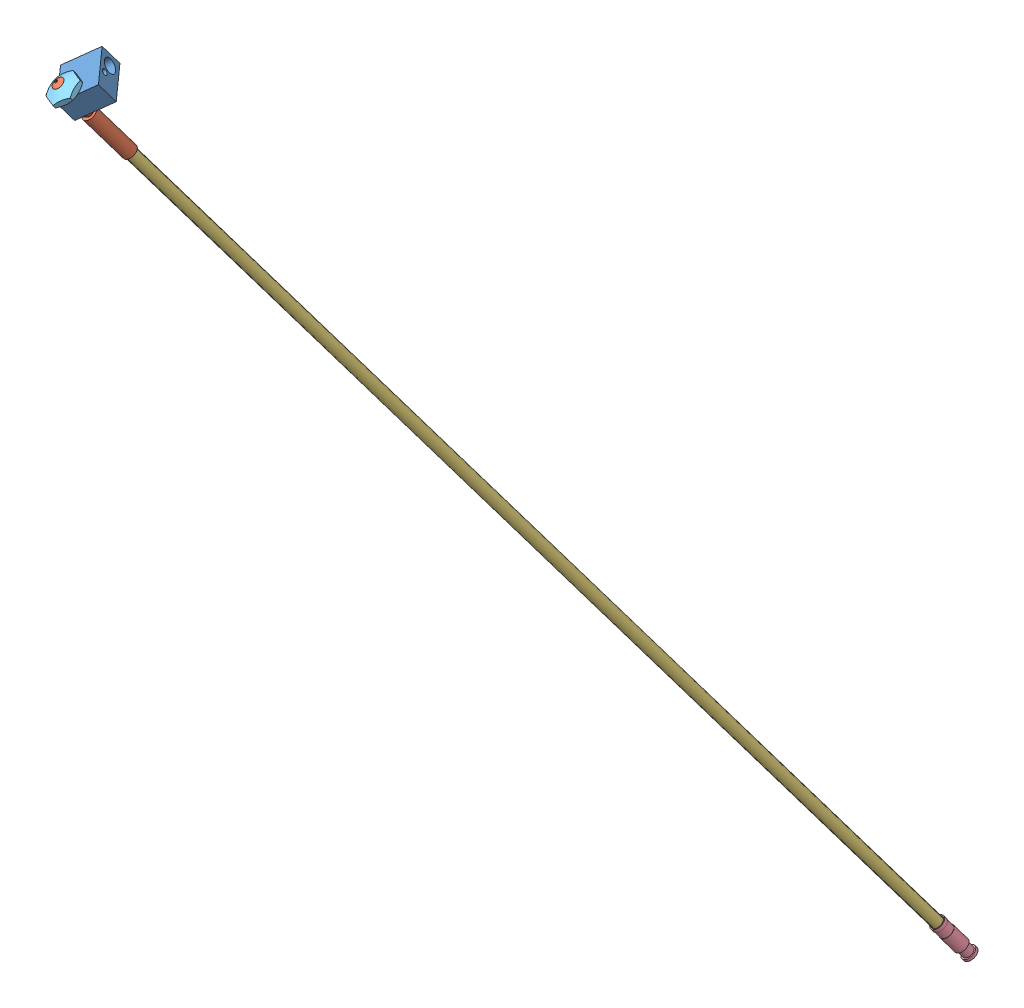
SolidWorks assembly 993, configuration SINGLE. Lengths in mm.
Overall size (146.61 331.74 220.5).
5 component instances, 5 part files, 89 mates.
Components (placement in the parent):
- 739-1: 739 [Default] at (90.2092 -3.5557 74.9658) x (-0.694987 -0.573024 0.434323) z (-0.330371 0.790997 0.514955)
- 738-2: 738 [Default] at (96.5193 -28.8096 77.071) x (0.082226 -0.519395 0.850569) z (-0.330371 0.790997 0.514955)
- 219-2: 219 [Default] at (219.3094 -322.8026 -114.3244) x (0.896188 0.091701 0.434094) z (-0.330371 0.790997 0.514955)
- 106-1: 106 [Default] at (216.207 -315.3746 -109.4887) x (0.541182 0.605747 -0.58326) z (0.330371 -0.790997 -0.514955)
- 794-1: 794 [Default] at (86.9463 -5.8894 91.9925) x (0.896188 0.091701 0.434094) z (-0.330371 0.790997 0.514955)
Mates (geometry in assembly coordinates):
- Coincident327: coincident anti-aligned: circle of 738-2; plane of ? through (56.8348 7.8683 60.6713) normal (-0.330371 0.790997 0.514955)
- Concentric245: concentric anti-aligned: cylinder of 739-1 through (86.9463 -5.8894 91.9925) axis (-0.330371 0.790997 0.514955) radius 1.65; cylinder of 738-2 through (96.5193 -28.8096 77.071) axis (0.330371 -0.790997 -0.514955) radius 2.5
- Concentric246: concentric anti-aligned: cylinder of ? through (58.2631 4.2288 58.0487) axis (-0.330371 0.790997 0.514955) radius 1.65; cylinder of ? through (67.8361 -18.6914 43.1272) axis (0.330371 -0.790997 -0.514955) radius 2
- Coincident331: coincident anti-aligned: plane of 739-1 through (99.15 -6.5573 85.3124) normal (0.330371 -0.790997 -0.514955); plane of 738-2 through (89.7784 -13.412 89.8292) normal (-0.330371 0.790997 0.514955)
- Coincident333: coincident anti-aligned: plane of ? through (59.0492 -34.3813 59.0199) normal (0.694987 0.573024 -0.434323); plane of ? through (59.0492 -34.3813 59.0199) normal (-0.694987 -0.573024 0.434323)
- Coincident335: coincident aligned: plane of 739-1 through (63.4764 -11.8319 70.5279) normal (0.330371 -0.790997 -0.514955); plane of ? through (51.3453 -7.7593 56.4895) normal (0.330371 -0.790997 -0.514955)
- Concentric259: concentric anti-aligned: cylinder of ? through (72.0249 -16.2373 53.0678) axis (-0.330371 0.790997 0.514955) radius 2.2; cylinder of ? through (70.0426 -11.4913 56.1575) axis (0.330371 -0.790997 -0.514955) radius 1.5
- Distance2: distance = 10 mm anti-aligned: plane of ? through (75.3286 -24.1473 47.9182) normal (-0.330371 0.790997 0.514955); plane of ? through (71.3313 -16.8108 53.5038) normal (0.330371 -0.790997 -0.514955)
- Coincident345: coincident anti-aligned: plane of ? through (59.0492 -34.3813 59.0199) normal (0.694987 0.573024 -0.434323); plane of ? through (59.0492 -34.3813 59.0199) normal (-0.694987 -0.573024 0.434323)
- Concentric263: concentric aligned: cylinder of ? through (38.6803 -22.3061 58.4748) axis (-0.694987 -0.573024 0.434323) radius 3.1; cylinder of ? through (47.0201 -15.4298 53.2629) axis (-0.694987 -0.573024 0.434323) radius 1.6
- Concentric264: concentric aligned: cylinder of ? through (59.1164 -29.1669 82.1241) axis (-0.694987 -0.573024 0.434323) radius 3.1; cylinder of ? through (67.4563 -22.2906 76.9122) axis (-0.694987 -0.573024 0.434323) radius 1.6
- Concentric265: concentric anti-aligned: cylinder of ? through (69.5412 -20.5715 75.6093) axis (0.694987 0.573024 -0.434323) radius 1.6; cylinder of ? through (59.1164 -29.1669 82.1241) axis (-0.694987 -0.573024 0.434323) radius 3.1
- Coincident355: coincident anti-aligned: plane of ? through (62.5241 -31.5162 56.8483) normal (-0.694987 -0.573024 0.434323); plane of ? through (62.5241 -31.5162 56.8483) normal (0.694987 0.573024 -0.434323)
- Concentric273: concentric anti-aligned: cylinder of ? through (49.1051 -13.7107 51.9599) axis (0.694987 0.573024 -0.434323) radius 1.6; cylinder of ? through (38.6803 -22.3061 58.4748) axis (-0.694987 -0.573024 0.434323) radius 3.1
- Concentric276: concentric aligned: cylinder of ? through (63.9813 -25.1557 79.0839) axis (-0.694987 -0.573024 0.434323) radius 1.6; cylinder of ? through (83.441 -9.111 66.9228) axis (-0.694987 -0.573024 0.434323) radius 1.5
- Coincident357: coincident anti-aligned: circle of ?; plane of ? through (59.1164 -29.1669 82.1241) normal (0.694987 0.573024 -0.434323)
- Concentric277: concentric aligned: cylinder of ? through (38.6803 -22.3061 58.4748) axis (-0.694987 -0.573024 0.434323) radius 3.1; cylinder of ? through (63.0048 -2.2503 43.2734) axis (-0.694987 -0.573024 0.434323) radius 1.5
- Coincident358: coincident anti-aligned: circle of ?; plane of ? through (38.6803 -22.3061 58.4748) normal (0.694987 0.573024 -0.434323)
- Concentric280: concentric aligned: cylinder of ? through (69.6883 -54.4788 65.6456) axis (-0.694987 -0.573024 0.434323) radius 3.1; circle of ?
- Coincident360: coincident anti-aligned: plane of ? through (52.0993 -40.1115 63.3631) normal (-0.694987 -0.573024 0.434323); plane of ? through (34.2827 -22.6016 57.9555) normal (0.694987 0.573024 -0.434323)
- Concentric284: concentric aligned: cylinder of ? through (67.8361 -18.6914 43.1272) axis (0.330371 -0.790997 -0.514955) radius 2.5; circle of ?
- Coincident361: coincident anti-aligned: plane of ? through (89.4855 -42.6667 55.3477) normal (0.694987 0.573024 -0.434323); plane of ? through (55.4841 -11.8694 41.5724) normal (-0.694987 -0.573024 0.434323)
- Concentric285: concentric anti-aligned: cylinder of ? through (77.1007 -15.9011 61.6336) axis (-0.330371 0.790997 0.514955) radius 2.5; cylinder of 738-2 through (79.9671 -22.764 57.1656) axis (0.330371 -0.790997 -0.514955) radius 2.5
- Concentric286: concentric anti-aligned: circle of ?; cylinder of ? through (67.8361 -18.6914 43.1272) axis (0.330371 -0.790997 -0.514955) radius 2.5
- Concentric287: concentric aligned: circle of ?; circle of ?
- Concentric288: concentric aligned: circle of ?; circle of ?
- Concentric289: concentric aligned: circle of ?; circle of ?
- Coincident362: coincident aligned: plane of ? through (61.6659 -3.9185 52.7446) normal (-0.330371 0.790997 0.514955); plane of ? through (62.34 -4.3458 53.8335) normal (-0.330371 0.790997 0.514955)
- Parallel3: parallel aligned: plane of ? through (81.665 -20.6588 71.8698) normal (0.63863 -0.214399 0.739043); plane of 739-1
- Coincident363: coincident anti-aligned: plane of ? through (64.9696 -11.8285 47.5951) normal (0.330371 -0.790997 -0.514955); plane of ? through (70.3402 -14.4378 55.0487) normal (-0.330371 0.790997 0.514955)
- Concentric290: concentric aligned: circle of ?; cylinder of ? through (75.4219 -49.7513 62.0624) axis (-0.694987 -0.573024 0.434323) radius 1.5
- Concentric291: concentric aligned: circle of ?; cylinder of ? through (58.009 -40.3979 36.5237) axis (-0.694987 -0.573024 0.434323) radius 1.5
- Coincident365: coincident aligned: plane of ? through (34.0047 -22.8308 58.1292) normal (-0.694987 -0.573024 0.434323); circle of ?
- Coincident366: coincident: cone of ? through (65.0357 -11.9867 47.4921) axis (-0.330371 0.790997 0.514955); circle of ?
- Concentric292: concentric aligned: cylinder of ? through (67.8361 -18.6914 43.1272) axis (0.330371 -0.790997 -0.514955) radius 2.5; cylinder of ? through (65.0853 -12.1055 47.4147) axis (0.330371 -0.790997 -0.514955) radius 2
- Concentric293: concentric aligned: cylinder of 738-2 through (96.5193 -28.8096 77.071) axis (0.330371 -0.790997 -0.514955) radius 1.75; cylinder of 219-2 through (93.7686 -22.2237 81.3586) axis (0.330371 -0.790997 -0.514955) radius 2
- Parallel4: parallel aligned: plane of ? through (86.5863 -15.8602 67.6562) normal (0.694987 0.573024 -0.434323); plane of ? through (74.8062 -13.9457 51.3322) normal (0.694987 0.573024 -0.434323)
- Coincident367: coincident aligned: plane of ? through (190.6262 -312.6844 -148.2683) normal (0.330371 -0.790997 -0.514955); plane of 219-2 through (202.7573 -316.757 -134.2298) normal (0.330371 -0.790997 -0.514955)
- Concentric294: concentric anti-aligned: cylinder of 219-2 through (93.7686 -22.2237 81.3586) axis (0.330371 -0.790997 -0.514955) radius 2; cylinder of 106-1 through (221.1626 -327.2396 -117.2131) axis (-0.330371 0.790997 0.514955) radius 2.5
- Coincident368: coincident: circle of 219-2; cone of 106-1 through (219.1803 -322.4936 -114.1233) axis (0.330371 -0.790997 -0.514955)
- Concentric295: concentric anti-aligned: cylinder of ? through (65.0853 -12.1055 47.4147) axis (0.330371 -0.790997 -0.514955) radius 2; cylinder of ? through (192.4794 -317.1214 -151.1569) axis (-0.330371 0.790997 0.514955) radius 2.5
- Coincident369: coincident aligned: plane of 106-1 through (204.6104 -321.194 -137.1184) normal (0.330371 -0.790997 -0.514955); plane of ? through (192.4794 -317.1214 -151.1569) normal (0.330371 -0.790997 -0.514955)
- Parallel7: parallel aligned: plane of 739-1; plane of ? through (57.6432 -4.4329 70.9557) normal (-0.694987 -0.573024 0.434323)
- Coincident370: coincident anti-aligned: plane of 739-1 through (96.5071 -0.2293 89.4321) normal (-0.330371 0.790997 0.514955); plane of 794-1 through (86.9463 -5.8894 91.9925) normal (0.330371 -0.790997 -0.514955)
- Concentric296: concentric aligned: cylinder of 738-2 through (96.5193 -28.8096 77.071) axis (0.330371 -0.790997 -0.514955) radius 2; circle of 794-1
- Concentric297: concentric aligned: circle of ?; cylinder of ? through (58.2631 4.2288 58.0487) axis (0.330371 -0.790997 -0.514955) radius 1.65
- Coincident371: coincident anti-aligned: plane of ? through (48.7024 -1.4313 60.6091) normal (-0.330371 0.790997 0.514955); plane of ? through (58.2631 4.2288 58.0487) normal (0.330371 -0.790997 -0.514955)
- Concentric298: concentric aligned: cylinder of ? through (67.6033 -56.1979 66.9485) axis (-0.694987 -0.573024 0.434323) radius 1.7; circle of ?
- Parallel10: parallel anti-aligned: plane of ? through (16.763 -88.5777 53.9549) normal (0.330371 -0.790997 -0.514955); plane of ? through (56.454 -52.6174 63.6171) normal (-0.330371 0.790997 0.514955)
- Coincident372: coincident anti-aligned: plane of ? through (34.0047 -22.8308 58.1292) normal (-0.694987 -0.573024 0.434323); plane of ? through (62.3013 -58.0048 57.0014) normal (0.694987 0.573024 -0.434323)
- Coincident373: coincident anti-aligned: plane of ? through (59.6256 -60.211 58.6735) normal (-0.694987 -0.573024 0.434323); circle of ?
- Concentric299: concentric anti-aligned: cylinder of ? through (75.4219 -49.7513 62.0624) axis (-0.694987 -0.573024 0.434323) radius 1.5; circle of ?
- Coincident374: coincident anti-aligned: plane of ? through (64.3021 -58.9197 69.0116) normal (0.694987 0.573024 -0.434323); plane of ? through (64.3021 -58.9197 69.0116) normal (-0.694987 -0.573024 0.434323)
- InPlace1: in place: plane of ? through (73.908 -8.6923 67.9314) normal (-0.330371 0.790997 0.514955); plane of ? through (-1.2187 2.918 1.8997) normal (-0.330371 0.790997 0.514955); moOrthogonalPlaneRef_w of ? through (73.908 -8.6923 67.9314) normal (-0.330371 0.790997 0.514955); unknown of ?; plane of ? through (73.908 -8.6923 67.9314) normal (-0.330371 0.790997 0.514955); unknown of ?; plane of 738-2 through (90.4602 -14.7379 87.8367) normal (-0.330371 0.790997 0.514955); unknown of ?
- Coincident375: coincident aligned: plane of 738-2; plane of ?
- Coincident376: coincident aligned: moOrthogonalPlaneRef_w of 738-2 through (90.3492 -14.0367 86.6884) normal (0.940263 0.323346 0.106552); plane of ?
- Coincident377: coincident anti-aligned: moOrthogonalPlaneRef_w of 738-2 through (90.3492 -14.0367 86.6884) normal (-0.082226 0.519395 -0.850569); plane of ?
- Concentric300: concentric anti-aligned: cylinder of 738-2 through (95.7529 -28.5523 76.1841) axis (0.330371 -0.790997 -0.514955) radius 2.5; cylinder of ? through (94.5384 -25.6444 78.0773) axis (-0.330371 0.790997 0.514955) radius 2.5
- Parallel11: parallel anti-aligned: plane of 739-1 through (86.7999 3.0295 78.1986) normal (-0.63863 0.214399 -0.739043); plane of ? through (118.1453 -17.4427 80.6243) normal (0.63863 -0.214399 0.739043)
- Coincident378: coincident aligned: plane of 738-2 through (89.6938 -14.4806 86.9499) normal (-0.330371 0.790997 0.514955); plane of ? through (103.6103 -2.3618 77.2629) normal (-0.330371 0.790997 0.514955)
- Coincident379: coincident anti-aligned: plane of ? through (118.1453 -17.4427 80.6243) normal (0.63863 -0.214399 0.739043); plane of ? through (124.8665 -36.8907 69.1743) normal (-0.63863 0.214399 -0.739043)
- Parallel12: parallel aligned: plane of ? through (103.6103 -2.3618 77.2629) normal (-0.330371 0.790997 0.514955); plane of ? through (112.1472 -6.4373 89.0001) normal (-0.330371 0.790997 0.514955)
- Coincident380: coincident aligned: plane of ? through (80.7663 -37.1477 86.9115) normal (-0.694987 -0.573024 0.434323); plane of ? through (85.8858 -29.6852 104.9491) normal (-0.694987 -0.573024 0.434323)
- Coincident381: coincident aligned: plane of ? through (103.6103 -2.3618 77.2629) normal (-0.330371 0.790997 0.514955); plane of ? through (112.1472 -6.4373 89.0001) normal (-0.330371 0.790997 0.514955)
- Coincident382: coincident anti-aligned: plane of ? through (107.5737 -41.1085 100.4843) normal (0.63863 -0.214399 0.739043); plane of ? through (107.5737 -41.1085 100.4843) normal (-0.63863 0.214399 -0.739043)
- Parallel13: parallel aligned: plane of ? through (108.5658 -14.2268 69.5386) normal (0.694987 0.573024 -0.434323); plane of ? through (127.8782 -10.509 105.3466) normal (0.694987 0.573024 -0.434323)
- Coincident383: coincident aligned: plane of ? through (108.5658 -14.2268 69.5386) normal (0.694987 0.573024 -0.434323); plane of ? through (127.8782 -10.509 105.3466) normal (0.694987 0.573024 -0.434323)
- Coincident384: coincident aligned: plane of ? through (103.6103 -2.3618 77.2629) normal (-0.330371 0.790997 0.514955); plane of ? through (100.0787 -33.4299 122.7195) normal (-0.330371 0.790997 0.514955)
- Parallel14: parallel anti-aligned: plane of ? through (103.6103 -2.3618 77.2629) normal (-0.330371 0.790997 0.514955); plane of ? through (113.1897 -5.5778 88.3486) normal (0.330371 -0.790997 -0.514955)
- Parallel15: parallel anti-aligned: plane of ? through (108.5658 -14.2268 69.5386) normal (0.694987 0.573024 -0.434323); plane of ? through (126.4045 -37.2177 67.7504) normal (-0.694987 -0.573024 0.434323)
- Parallel16: parallel aligned: plane of ? through (118.2406 -42.3538 73.315) normal (-0.63863 0.214399 -0.739043); plane of ? through (77.8476 -105.4504 83.1499) normal (-0.63863 0.214399 -0.739043)
- Coincident387: coincident anti-aligned: plane of ? through (114.9521 -16.3707 76.929) normal (0.63863 -0.214399 0.739043); plane of ? through (84.4734 -99.9873 79.0091) normal (-0.63863 0.214399 -0.739043)
- Coincident388: coincident anti-aligned: plane of ? through (119.2831 -41.4943 72.6636) normal (0.694987 0.573024 -0.434323); plane of ? through (119.7787 -42.6808 71.8911) normal (-0.694987 -0.573024 0.434323)
- Coincident389: coincident anti-aligned: plane of ? through (93.0217 -64.7422 88.6126) normal (0.330371 -0.790997 -0.514955); plane of ? through (119.7787 -42.6808 71.8911) normal (-0.330371 0.790997 0.514955)
- Coincident390: coincident: plane of ? through (87.6666 -101.0593 82.7044) normal (0.63863 -0.214399 0.739043); plane of ? through (83.9318 -33.9548 105.399) normal (-0.63863 0.214399 -0.739043)
- Concentric301: concentric aligned: cylinder of ? through (78.4807 -32.1248 99.0909) axis (0.63863 -0.214399 0.739043) radius 1.25; cylinder of ? through (74.033 -30.6316 93.9438) axis (0.63863 -0.214399 0.739043) radius 1.5
- Coincident391: coincident anti-aligned: plane of ? through (87.6666 -101.0593 82.7044) normal (0.63863 -0.214399 0.739043); plane of ? through (83.9318 -33.9548 105.399) normal (-0.63863 0.214399 -0.739043)
- Concentric302: concentric aligned: circle of ?; cylinder of ? through (76.2682 -31.382 96.5305) axis (0.63863 -0.214399 0.739043) radius 1.5
- Coincident392: coincident anti-aligned: plane of ? through (87.6666 -101.0593 82.7044) normal (0.63863 -0.214399 0.739043); plane of ? through (117.2911 -6.4497 84.5515) normal (-0.63863 0.214399 -0.739043)
- Concentric303: concentric aligned: circle of ?; cylinder of ? through (109.6276 -3.8769 75.683) axis (0.63863 -0.214399 0.739043) radius 1.5
- Coincident393: coincident aligned: plane of ? through (95.6384 -39.1217 120.846) normal (0.63863 -0.214399 0.739043); circle of ?
- Concentric304: concentric anti-aligned: circle of ?; cylinder of ? through (76.4795 -32.6898 98.6747) axis (0.63863 -0.214399 0.739043) radius 1.5
- Coincident394: coincident aligned: plane of ? through (117.878 -20.785 106.9477) normal (0.63863 -0.214399 0.739043); circle of ?
- Concentric305: concentric aligned: cylinder of ? through (113.4076 -19.2842 101.7744) axis (0.63863 -0.214399 0.739043) radius 1.6; cylinder of ? through (101.9122 -15.425 88.4716) axis (0.63863 -0.214399 0.739043) radius 1.5
- Coincident395: coincident anti-aligned: plane of ? through (118.2406 -42.3538 73.315) normal (-0.63863 0.214399 -0.739043); plane of ? through (92.6628 -22.5025 101.1766) normal (0.63863 -0.214399 0.739043)
- Concentric306: concentric aligned: cylinder of ? through (101.9122 -15.425 88.4716) axis (0.63863 -0.214399 0.739043) radius 1.5; cylinder of ? through (98.7191 -14.353 84.7764) axis (0.63863 -0.214399 0.739043) radius 1.25
- Concentric307: concentric aligned: cylinder of ? through (76.4795 -32.6898 98.6747) axis (0.63863 -0.214399 0.739043) radius 1.5; cylinder of ? through (76.4795 -32.6898 98.6747) axis (0.63863 -0.214399 0.739043) radius 1.25
- Concentric308: concentric anti-aligned: cylinder of 738-2 through (96.5193 -28.8096 77.071) axis (0.330371 -0.790997 -0.514955) radius 2.5; cylinder of ? through (93.6529 -21.9466 81.5389) axis (-0.330371 0.790997 0.514955) radius 2.5
- Concentric309: concentric aligned: circle of ?; cylinder of ? through (101.9122 -15.425 88.4716) axis (0.63863 -0.214399 0.739043) radius 1.5
